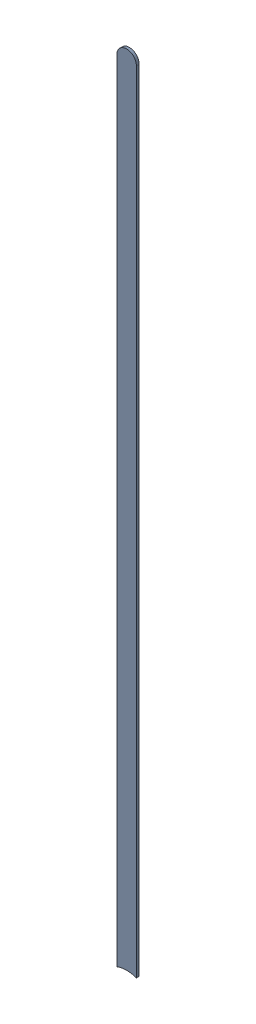
SolidWorks assembly Track (21.9mm,40mm)(21.9mm,50.6mm) on Top Layer, configuration Predeterminado. Lengths in mm.
Overall size (0.25 10.39 0.04).
2 component instances, 1 part files, 0 mates.
Components (placement in the parent):
- Track (21.9mm,40mm)(21.9mm,50.6mm) on Top Layer-1-1: Track (21.9mm,40mm)(21.9mm,50.6mm) on Top Layer-1 [Predeterminado] at (-68.317 -44.187 -0.0457) size (0.25 10.39 0.04)
  - Track (21.9mm,40mm)(21.9mm,50.6mm) on Top Layer-Part-1-1: Track (21.9mm,40mm)(21.9mm,50.6mm) on Top Layer-Part-1 [Predeterminado] at origin size (0.25 10.39 0.04)
